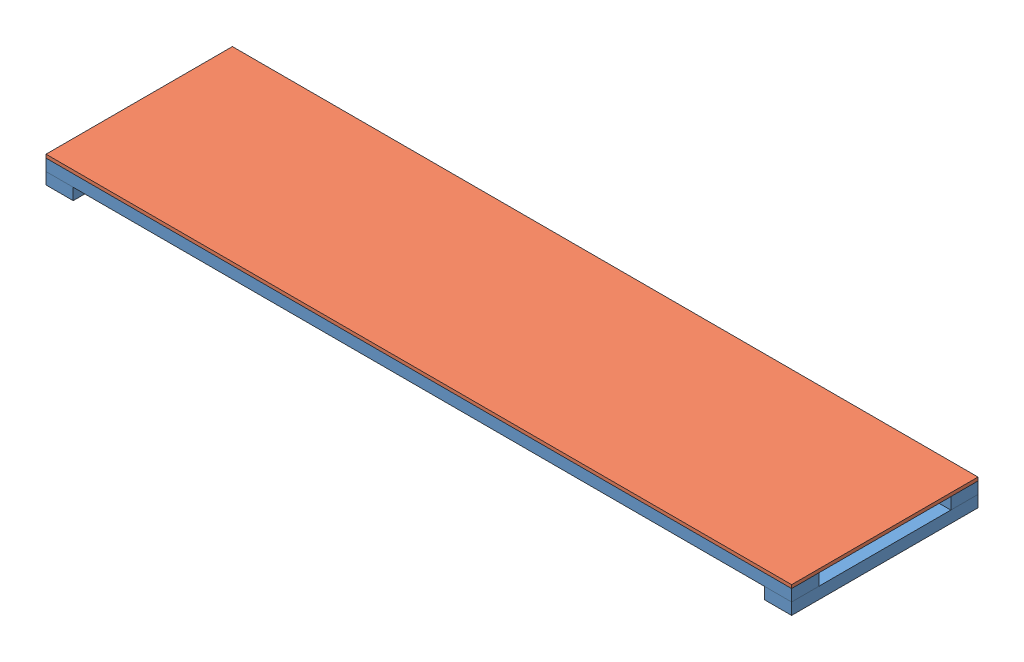
SolidWorks assembly Printers, configuration Default. Lengths in mm.
Overall size (2438.4 87.31 609.6).
5 component instances, 2 part files, 14 mates.
Components (placement in the parent):
- 2x4_Printers-1: 2x4_Printers [2ft] at (-114.7784 -35.2323 -256.6946) size (88.9 38.1 609.6)
- 2x4_Printers-2: 2x4_Printers [8ft] at (2323.6216 2.8677 -256.6946) x (0 0 1) z (-1 0 0) size (88.9 38.1 2438.4)
- 2x4_Printers-3: 2x4_Printers [8ft] at (-114.7784 2.8677 352.9054) x (0 0 -1) z (1 0 0) size (88.9 38.1 2438.4)
- 2x4_Printers-4: 2x4_Printers [2ft] at (2234.7216 -35.2323 -256.6946) size (88.9 38.1 609.6)
- Plywood_Printers-1: Plywood_Printers [2ftX8ft] at (2323.6216 52.0802 -256.6946) x (0 0 1) z (0 -1 0) size (609.6 2438.4 11.11)
Mates (geometry in assembly coordinates):
- Coincident10: coincident anti-aligned: plane of 2x4_Printers-1 through (-114.7784 2.8677 352.9054) normal (0 1 0); plane of 2x4_Printers-3 through (2323.6216 2.8677 352.9054) normal (0 -1 0)
- Coincident12: coincident aligned: plane of 2x4_Printers-1 through (-114.7784 -35.2323 352.9054) normal (0 0 1); plane of 2x4_Printers-3 through (2323.6216 2.8677 352.9054) normal (0 0 1)
- Coincident13: coincident aligned: plane of 2x4_Printers-1 through (-114.7784 -35.2323 352.9054) normal (-1 0 0); plane of 2x4_Printers-3 through (-114.7784 2.8677 352.9054) normal (-1 0 0)
- Coincident14: coincident anti-aligned: plane of 2x4_Printers-1 through (-114.7784 2.8677 352.9054) normal (0 1 0); plane of 2x4_Printers-2 through (-114.7784 2.8677 -256.6946) normal (0 -1 0)
- Coincident15: coincident aligned: plane of 2x4_Printers-1 through (-114.7784 -35.2323 -256.6946) normal (0 0 -1); plane of 2x4_Printers-2 through (-114.7784 2.8677 -256.6946) normal (0 0 -1)
- Coincident16: coincident aligned: plane of 2x4_Printers-1 through (-114.7784 -35.2323 352.9054) normal (-1 0 0); plane of 2x4_Printers-2 through (-114.7784 2.8677 -256.6946) normal (-1 0 0)
- Coincident17: coincident aligned: plane of 2x4_Printers-2 through (-114.7784 2.8677 -256.6946) normal (0 0 -1); plane of 2x4_Printers-4 through (2234.7216 -35.2323 -256.6946) normal (0 0 -1)
- Coincident18: coincident aligned: plane of 2x4_Printers-2 through (2323.6216 2.8677 -256.6946) normal (1 0 0); plane of 2x4_Printers-4 through (2323.6216 -35.2323 352.9054) normal (1 0 0)
- Coincident19: coincident aligned: plane of 2x4_Printers-3 through (2323.6216 2.8677 352.9054) normal (1 0 0); plane of 2x4_Printers-4 through (2323.6216 -35.2323 352.9054) normal (1 0 0)
- Coincident20: coincident aligned: plane of 2x4_Printers-3 through (2323.6216 2.8677 352.9054) normal (0 0 1); plane of 2x4_Printers-4 through (2234.7216 -35.2323 352.9054) normal (0 0 1)
- Coincident21: coincident anti-aligned: plane of 2x4_Printers-3 through (2323.6216 2.8677 352.9054) normal (0 -1 0); plane of 2x4_Printers-4 through (2234.7216 2.8677 352.9054) normal (0 1 0)
- Coincident22: coincident: plane of 2x4_Printers-3 through (2323.6216 40.9677 352.9054) normal (0 1 0); plane of Plywood_Printers-1 through (2026.4603 40.9677 -256.6946) normal (0 -1 0)
- Coincident23: coincident: plane of 2x4_Printers-3 through (2323.6216 2.8677 352.9054) normal (0 0 1); plane of Plywood_Printers-1 through (2323.6216 40.9677 352.9054) normal (0 0 1)
- Coincident24: coincident aligned: plane of 2x4_Printers-3 through (2323.6216 2.8677 352.9054) normal (1 0 0); plane of Plywood_Printers-1 through (2323.6216 40.9677 -256.6946) normal (1 0 0)
